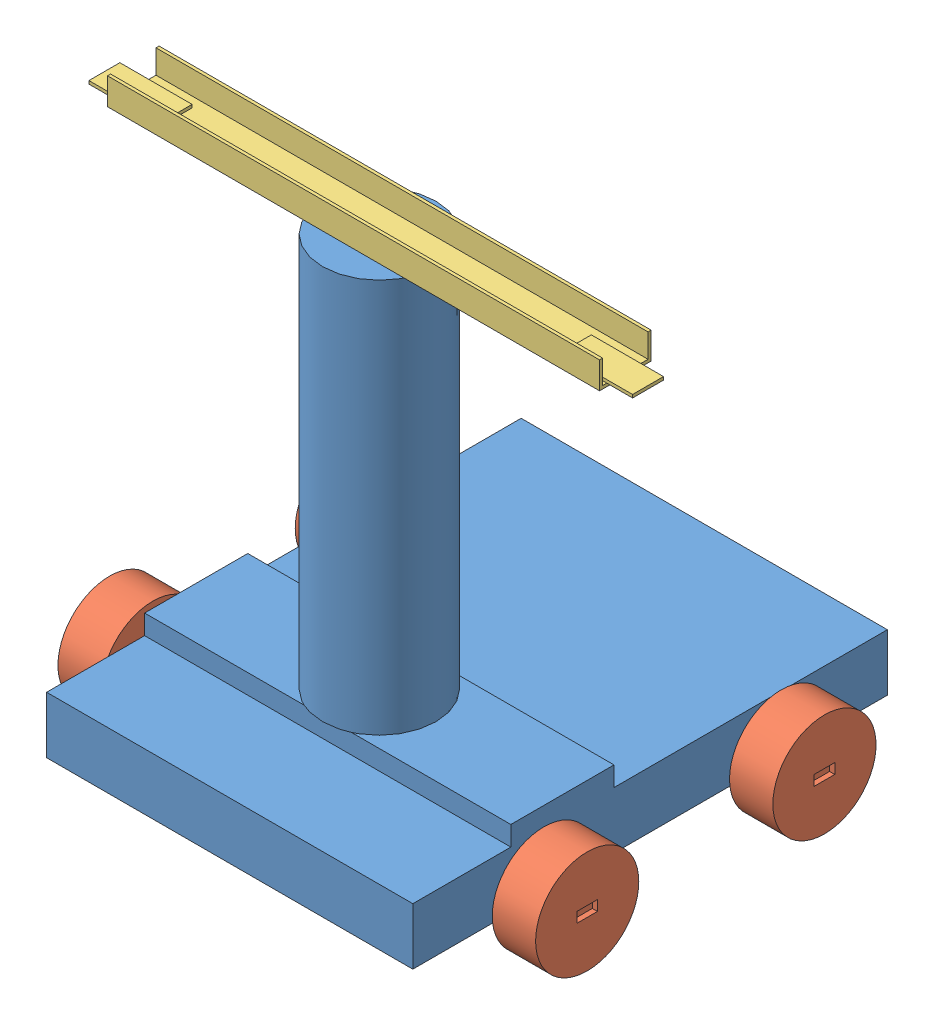
SolidWorks assembly Chassis-03, configuration Default. Lengths in mm.
Overall size (527 514 460).
6 component instances, 3 part files, 11 mates.
Components (placement in the parent):
- Base-Part-01-1: Base-Part-01 [Default] at (-177.5 0 145) x (1 0 0) z (0 1 0) size (399 460 456)
- Base-Wheel-01-1: Base-Wheel-01 [Default] at (189.5 50 30) x (0 0 1) z (1 0 0) size (100 100 42)
- Base-Wheel-01-2: Base-Wheel-01 [Default] at (189.5 50 -200) x (0 0 1) z (1 0 0) size (100 100 42)
- Base-Wheel-01-3: Base-Wheel-01 [Default] at (-189.5 50 30) x (0 0 1) z (-1 0 0) size (100 100 42)
- Base-Wheel-01-4: Base-Wheel-01 [Default] at (-189.5 50 -200) x (0 0 1) z (-1 0 0) size (100 100 42)
- Base-Top-02-1: Base-Top-02 [Default] at (-177.5 0 145) x (1 0 0) z (0 1 0) size (527 50 36)
Mates (geometry in assembly coordinates):
- Concentric3: concentric aligned: cylinder of Base-Part-01-1 through (199.5 50 30) axis (-1 0 0) radius 4; cylinder of Base-Wheel-01-1 through (199.5 50 30) axis (-1 0 0) radius 4
- Coincident2: coincident anti-aligned: plane of Base-Part-01-1 through (199.5 50 30) normal (1 0 0); plane of Base-Wheel-01-1 through (199.5 50 30) normal (-1 0 0)
- Concentric4: concentric aligned: cylinder of Base-Part-01-1 through (199.5 50 -200) axis (-1 0 0) radius 4; cylinder of Base-Wheel-01-2 through (199.5 50 -200) axis (-1 0 0) radius 4
- Coincident3: coincident anti-aligned: plane of Base-Part-01-1 through (199.5 0 145) normal (1 0 0); plane of Base-Wheel-01-2 through (199.5 50 -200) normal (-1 0 0)
- Concentric5: concentric aligned: cylinder of Base-Part-01-1 through (-199.5 50 -200) axis (1 0 0) radius 4; cylinder of Base-Wheel-01-4 through (-199.5 50 -200) axis (1 0 0) radius 4
- Coincident4: coincident anti-aligned: plane of Base-Part-01-1 through (-199.5 50 -200) normal (-1 0 0); plane of Base-Wheel-01-4 through (-199.5 50 -200) normal (1 0 0)
- Concentric6: concentric aligned: cylinder of Base-Part-01-1 through (-199.5 50 30) axis (1 0 0) radius 4; cylinder of Base-Wheel-01-3 through (-199.5 50 30) axis (1 0 0) radius 4
- Coincident5: coincident anti-aligned: plane of Base-Part-01-1 through (-199.5 50 30) normal (-1 0 0); plane of Base-Wheel-01-3 through (-199.5 50 30) normal (1 0 0)
- Coincident6: coincident anti-aligned: plane of Base-Part-01-1 through (10 478 -10) normal (0 0 1); plane of Base-Top-02-1 through (10 478 -10) normal (0 0 -1)
- Coincident7: coincident anti-aligned: plane of Base-Part-01-1 through (10 478 -25) normal (-1 0 0); plane of Base-Top-02-1 through (10 478 10) normal (1 0 0)
- Coincident8: coincident anti-aligned: plane of Base-Part-01-1 through (-177.5 478 145) normal (0 1 0); plane of Base-Top-02-1 through (-177.5 478 145) normal (0 -1 0)
